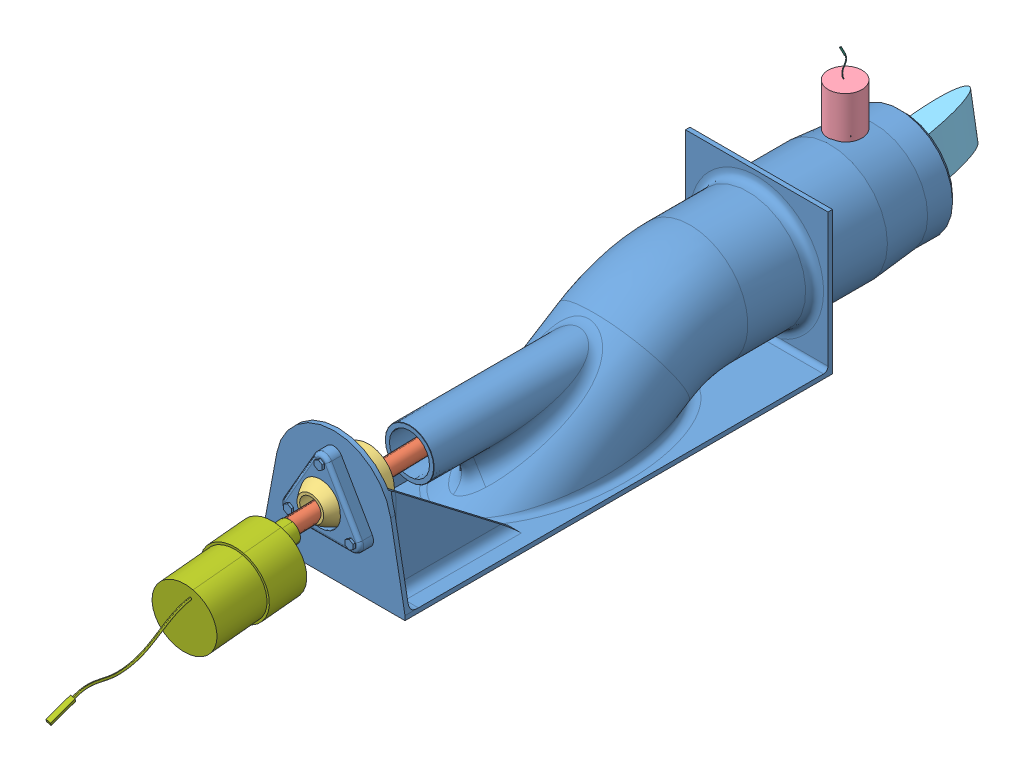
SolidWorks assembly Assem2, configuration Default. Lengths in mm.
Overall size (23.46 45.38 154.61).
8 component instances, 7 part files, 6 mates.
Components (placement in the parent):
- Assem1-1: Assem1 [Default] at (92.4561 -44.6114 -18.4795) size (23.46 36.36 96.35)
  - DW1_PumpBodyv1-1: DW1_PumpBodyv1 [Default] at (-76.5332 41.6501 9.0028) size (23.46 36.36 96.35)
- DW1_Driveshaftv1-1: DW1_Driveshaftv1 [Default] at (4.7329 1.5113 -453.6541) x (0.999692 0.010056 -0.022673) z (0.022726 -0.005146 0.999728) size (2.58 2.58 92.72)
- DW1_Impeller-1: DW1_Impeller [Default] at (15.0661 -0.196 10.564) x (0.779682 -0.62579 -0.021994) z (-0.027063 0.001414 -0.999633) size (11.86 11.82 91.49)
- motor cover-1: motor cover [Default] at (77.473 -25.8002 -34.1276) size (5.55 6.91 5.55)
- Rudder-1: Rudder [Default] at (-0.1238 109.0309 -111.2397) x (0.001044 -0.989611 -0.143766) z (-0.328288 0.135459 -0.934814) size (16.09 8.33 20.3)
- motor.step-1: motor.step [Default] at (13.1786 38.0618 -43.6454) x (0.830617 0.051608 0.554447) z (0.553554 0.031552 -0.832216) size (3.13 12.79 3.13)
- motor.step2-1: motor.step2 [Default] at (16.9997 -6.4369 85.8641) x (0.951124 -0.303012 -0.05955) z (0.305107 0.951853 0.029749) size (10.94 44.77 10.94)
Mates (geometry in assembly coordinates):
- Lock5: lock: unknown of motor cover-1; unknown of Rudder-1
- Lock6: lock: unknown of Assem1-1/DW1_PumpBodyv1-1; unknown of motor cover-1
- Lock7: lock: unknown of Assem1-1/DW1_PumpBodyv1-1; unknown of Rudder-1
- Lock10: lock: unknown of DW1_Driveshaftv1-1; unknown of DW1_Impeller-1
- Lock11: lock: unknown of Assem1-1/DW1_PumpBodyv1-1; unknown of DW1_Driveshaftv1-1
- Lock12: lock: unknown of DW1_Driveshaftv1-1; unknown of motor.step2-1
